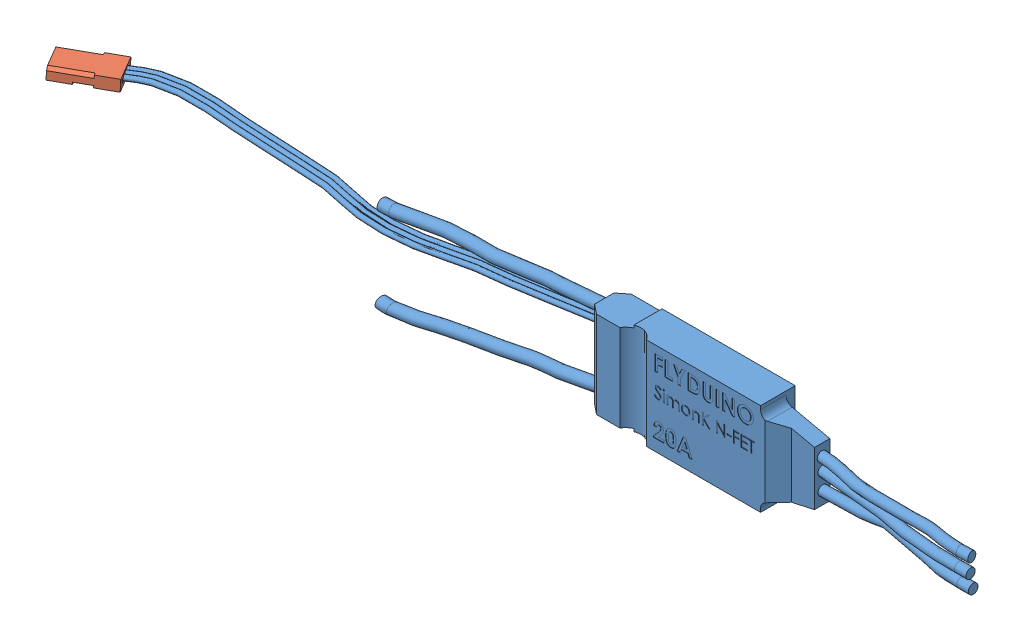
SolidWorks assembly 28-2-2013-100 - ESC Flyduino SimonK 20A, configuration Default. Lengths in mm.
Overall size (234.51 28.36 18.72).
2 component instances, 2 part files, 3 mates.
Components (placement in the parent):
- 28-2-2013-001 - ESC Flyduino SimonK 20A body-1: 28-2-2013-001 - ESC Flyduino SimonK 20A body [Default] at origin size (224.06 28.36 11.1)
- 28-2-2013-002 - ESC 3-pin connector-1: 28-2-2013-002 - ESC 3-pin connector [Default] at (-148.781 2.8539 7.8603) x (-0.523991 -0.063525 -0.849352) z (0.007034 -0.997503 0.070267) size (8.1 14 2.8)
Mates (geometry in assembly coordinates):
- Concentric1: concentric anti-aligned: circle of 28-2-2013-001 - ESC Flyduino SimonK 20A body-1; cylinder of 28-2-2013-002 - ESC 3-pin connector-1 through (-153.0395 3.0081 10.4759) axis (0.851695 -0.030845 -0.523129) radius 0.45
- Coincident1: coincident anti-aligned: circle of 28-2-2013-001 - ESC Flyduino SimonK 20A body-1; plane of 28-2-2013-002 - ESC 3-pin connector-1 through (-148.781 2.8539 7.8603) normal (0.851695 -0.030845 -0.523129)
- Distance1: distance = 1.3 mm: line of 28-2-2013-002 - ESC 3-pin connector-1 through (-150.913 3.9931 4.322) axis (0.523991 0.063525 0.849352); moEndPointRef_w of 28-2-2013-001 - ESC Flyduino SimonK 20A body-1
